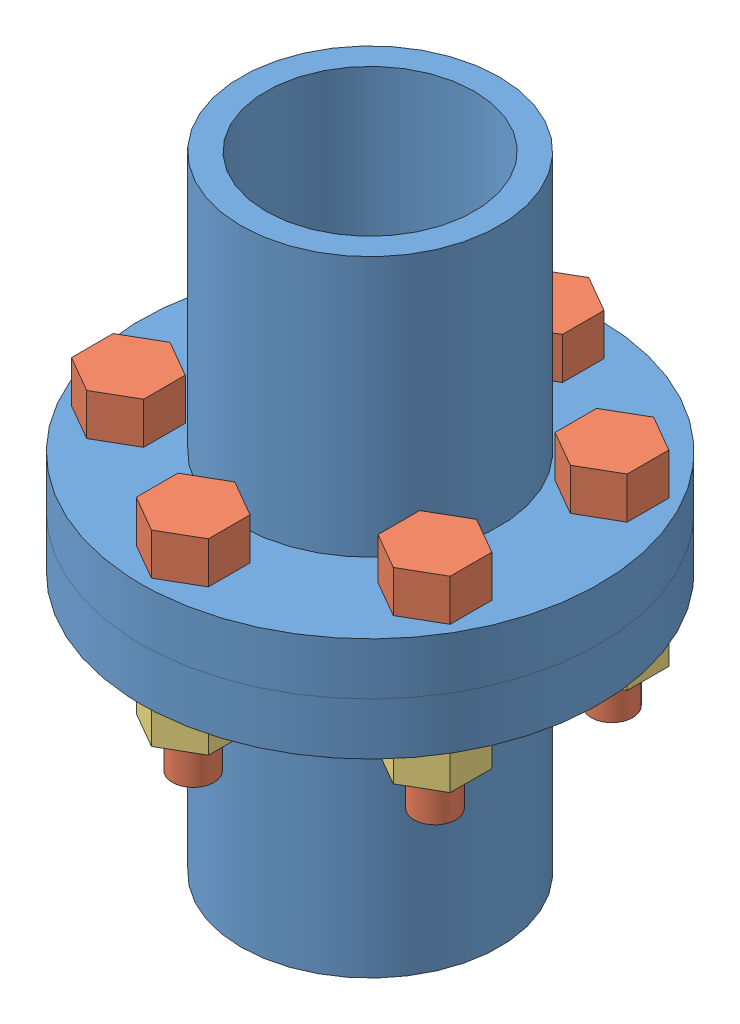
SolidWorks assembly maniAssem2, configuration Default. Lengths in mm.
Overall size (220 300 220).
14 component instances, 3 part files, 5 mates.
Components (placement in the parent):
- manish flangePart1-1: manish flangePart1 [Default] at (224.8218 216.7508 220.3297) x (-1 0 0) z (0 0 1) size (220 150 220)
- manish flangePart1-3: manish flangePart1 [Default] at (224.8218 216.7508 220.3297) size (220 150 220)
- manish bolt Part1-1: manish bolt Part1 [Default] at (298.434 151.7508 177.8297) size (34.64 110 50)
- manish bolt Part2-1: manish bolt Part2 [Default] at (298.434 171.7508 177.8297) size (34.64 20 40)
- manish bolt Part1-13: manish bolt Part1 [Default] at (298.434 151.7508 262.8297) x (0.5 0 0.866025) z (-0.866025 0 0.5) size (34.64 110 50)
- manish bolt Part1-14: manish bolt Part1 [Default] at (224.8218 151.7508 305.3297) x (-0.5 0 0.866025) z (-0.866025 0 -0.5) size (34.64 110 50)
- manish bolt Part1-15: manish bolt Part1 [Default] at (151.2097 151.7508 262.8297) x (-1 0 0) z (0 0 -1) size (34.64 110 50)
- manish bolt Part1-16: manish bolt Part1 [Default] at (151.2097 151.7508 177.8297) x (-0.5 0 -0.866025) z (0.866025 0 -0.5) size (34.64 110 50)
- manish bolt Part1-17: manish bolt Part1 [Default] at (224.8218 151.7508 135.3297) x (0.5 0 -0.866025) z (0.866025 0 0.5) size (34.64 110 50)
- manish bolt Part2-13: manish bolt Part2 [Default] at (298.434 171.7508 262.8297) x (0.5 0 0.866025) z (-0.866025 0 0.5) size (34.64 20 40)
- manish bolt Part2-14: manish bolt Part2 [Default] at (224.8218 171.7508 305.3297) x (-0.5 0 0.866025) z (-0.866025 0 -0.5) size (34.64 20 40)
- manish bolt Part2-15: manish bolt Part2 [Default] at (151.2097 171.7508 262.8297) x (-1 0 0) z (0 0 -1) size (34.64 20 40)
- manish bolt Part2-16: manish bolt Part2 [Default] at (151.2097 171.7508 177.8297) x (-0.5 0 -0.866025) z (0.866025 0 -0.5) size (34.64 20 40)
- manish bolt Part2-17: manish bolt Part2 [Default] at (224.8218 171.7508 135.3297) x (0.5 0 -0.866025) z (0.866025 0 0.5) size (34.64 20 40)
Mates (geometry in assembly coordinates):
- Coincident4: coincident aligned: axis of manish flangePart1-1 through (224.8218 66.7508 220.3297) axis (0 1 0); axis of manish flangePart1-3 through (224.8218 216.7508 220.3297) axis (0 1 0)
- Coincident5: coincident anti-aligned: plane of manish flangePart1-1 through (224.8218 216.7508 220.3297) normal (0 1 0); plane of manish flangePart1-3 through (224.8218 216.7508 220.3297) normal (0 -1 0)
- Coincident10: coincident anti-aligned: plane of manish flangePart1-3 through (224.8218 241.7508 220.3297) normal (0 1 0); plane of manish bolt Part1-1 through (298.434 241.7508 177.8297) normal (0 -1 0)
- Concentric3: concentric anti-aligned: axis of manish bolt Part1-1 through (298.434 241.7508 177.8297) axis (0 -1 0); cylinder of manish bolt Part2-1 through (298.434 171.7508 177.8297) axis (0 1 0) radius 10
- Coincident13: coincident anti-aligned: plane of manish flangePart1-1 through (224.8218 191.7508 220.3297) normal (0 -1 0); plane of manish bolt Part2-1 through (298.434 191.7508 177.8297) normal (0 1 0)
